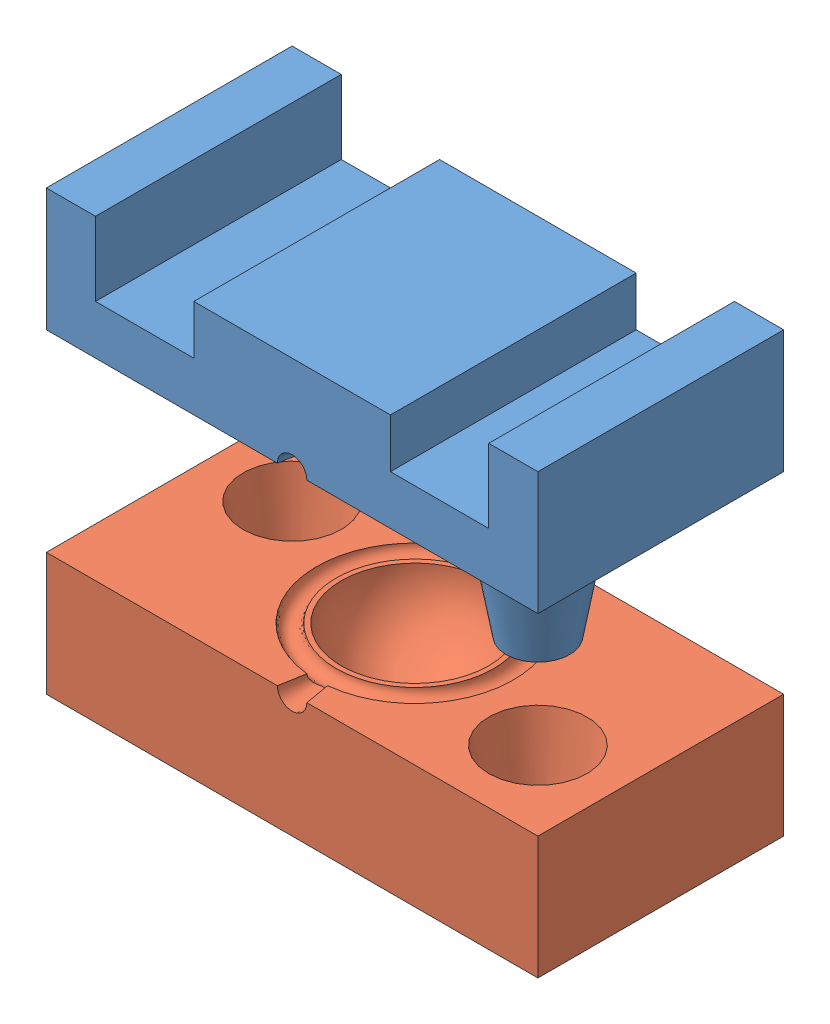
SolidWorks assembly Assemblage1, configuration Défaut. Lengths in mm.
Overall size (50 44.6 25).
2 component instances, 2 part files, 2 mates.
Components (placement in the parent):
- moule_femelle_collier-1: moule_femelle_collier [Défaut] at origin size (50 22.5 25)
- moule_male_collier-1: moule_male_collier [Défaut] at (0 -44.6018 0) size (50 12.58 25)
Mates (geometry in assembly coordinates):
- Coïncidente4: coincident aligned: plane of moule_femelle_collier-1 through (25 -12.5 12.5) normal (1 0 0); plane of moule_male_collier-1 through (25 -32.1018 -12.5) normal (1 0 0)
- Coïncidente3: coincident: plane of moule_femelle_collier-1 through (25 -12.5 -12.5) normal (0 0 -1); plane of moule_male_collier-1 through (-24.1557 -32.1018 -12.5) normal (0 0 -1)
